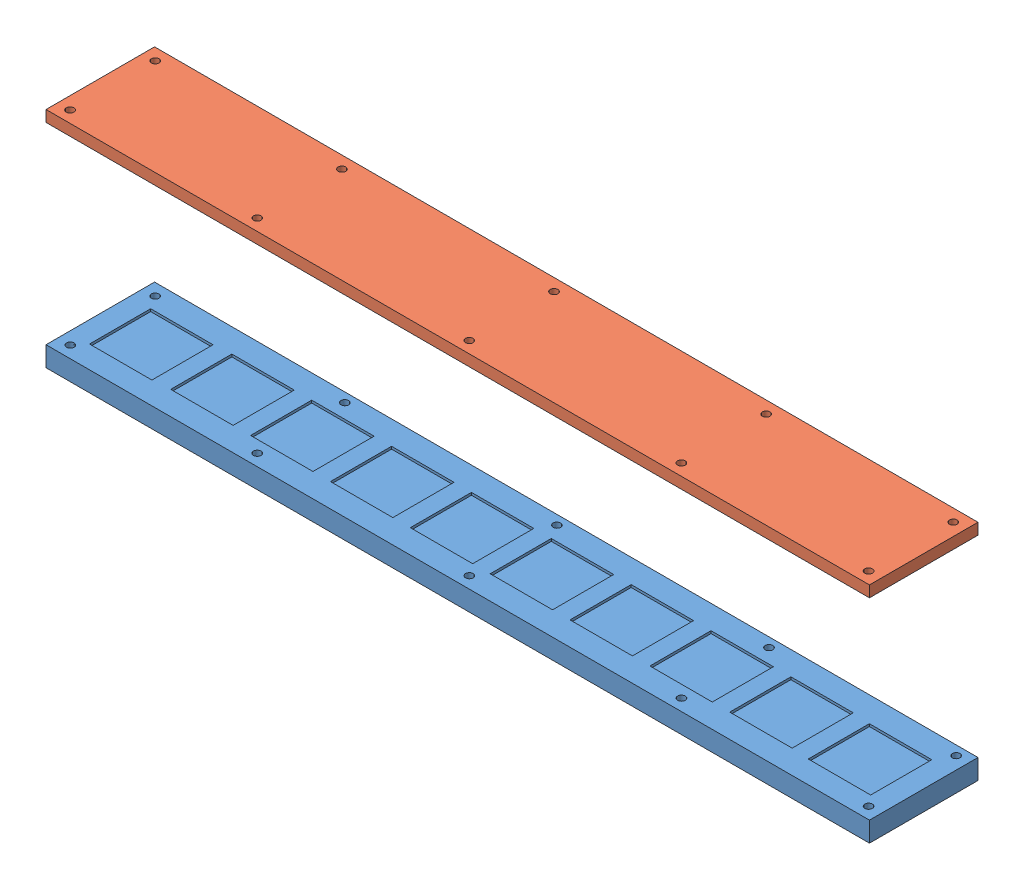
SolidWorks assembly Assem1 chip case, configuration Default. Lengths in mm.
Overall size (330 89.64 43.5).
2 component instances, 2 part files, 3 mates.
Components (placement in the parent):
- chip case-1: chip case [Default] at (123.6922 -32.9763 -42.8671) size (330 8 43.5)
- Chip case cover-1: Chip case cover [Default] at (123.6922 52.1649 -42.8671) size (330 4.5 43.5)
Mates (geometry in assembly coordinates):
- Coincident1: coincident aligned: plane of chip case-1 through (-206.3078 -24.9763 -42.8671) normal (-1 0 0); plane of Chip case cover-1 through (-206.3078 56.6649 -42.8671) normal (-1 0 0)
- Coincident2: coincident aligned: plane of chip case-1 through (123.6922 -24.9763 -42.8671) normal (0 0 1); plane of Chip case cover-1 through (123.6922 56.6649 -42.8671) normal (0 0 1)
- Coincident3: coincident aligned: plane of chip case-1 through (123.6922 -24.9763 -86.3671) normal (0 0 -1); plane of Chip case cover-1 through (123.6922 56.6649 -86.3671) normal (0 0 -1)
